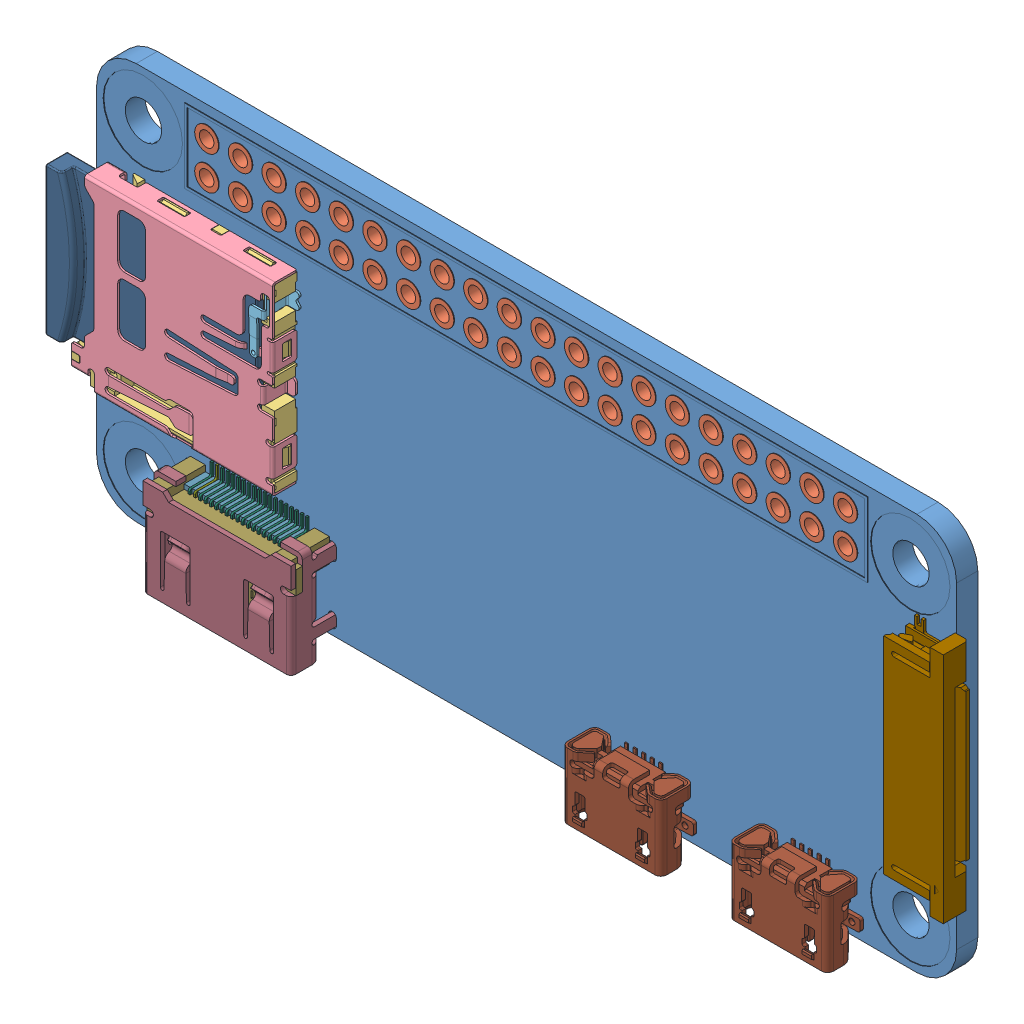
SolidWorks assembly rpi-zero, configuration Default. Lengths in mm.
Overall size (67.36 31 5.45).
80 component instances, 16 part files, 26 mates.
Components (placement in the parent):
- rpi-zero-board-2: rpi-zero-board [Default] at (32.5 15 0) size (65 30 1.65)
- rpi-zero-pin-header-pad-41: rpi-zero-pin-header-pad [Default] at (8.37 27.77 0.8) size (1.8 1.8 1.7)
- rpi-zero-micro-sd-slot.step-1: rpi-zero-micro-sd-slot.step [Default] at (7.6 15.665 1.65) x (0 1 0) z (1 0 0) size (14.1 1.9 15.45)
  - microSD_Body.step-1: microSD_Body.step [Default] at origin size (14.1 1.85 15.2)
  - microSD_Cover.step-1: microSD_Cover.step [Default] at (0 1.7 0) x (1 0 0) z (0 0 -1) size (13.95 1.9 15.2)
  - microSD_Card_Detect.step-1: microSD_Card_Detect.step [Default] at (4.99 -0.05 7.4) size (4.45 1.9 2.05)
  - microSD_Pin_11.15.step-1: microSD_Pin_11.15.step [Default] at (5.725 0 -2) x (0 0 1) z (-1 0 0) size (7.35 1.18 0.6)
  - microSD_Pin_11.15.step-2: microSD_Pin_11.15.step [Default] at (4.625 0 -2) x (0 0 1) z (-1 0 0) size (7.35 1.18 0.6)
  - microSD_Pin_11.35.step-1: microSD_Pin_11.35.step [Default] at (3.525 0 -2) x (0 0 1) z (-1 0 0) size (7.35 1.18 0.6)
  - microSD_Pin_11.15.step-3: microSD_Pin_11.15.step [Default] at (2.425 0 -2) x (0 0 1) z (-1 0 0) size (7.35 1.18 0.6)
  - microSD_Pin_11.35.step-2: microSD_Pin_11.35.step [Default] at (1.325 0 -2) x (0 0 1) z (-1 0 0) size (7.35 1.18 0.6)
  - microSD_Pin_11.15.step-4: microSD_Pin_11.15.step [Default] at (0.225 0 -2) x (0 0 1) z (-1 0 0) size (7.35 1.18 0.6)
  - microSD_Pin_10.75.step-1: microSD_Pin_10.75.step [Default] at (-0.875 0 -2) x (0 0 1) z (-1 0 0) size (7.25 1.18 0.6)
  - microSD_Pin_11.15.step-5: microSD_Pin_11.15.step [Default] at (-1.975 0 -2) x (0 0 1) z (-1 0 0) size (7.35 1.18 0.6)
- rpi-zero-fpc-connector.stp-1: rpi-zero-fpc-connector.stp [Default] at (61.5 15 1.61) x (0 1 0) z (1 0 0) size (17.6 2.04 5.2)
- rpi-zero-micro-sd.stp-3: rpi-zero-micro-sd.stp [Default] at (6.17 16.9 2.45) x (1 0 0) z (0 -1 0) size (15.06 1.66 11.19)
- rpi-zero-pin-header-pad-42: rpi-zero-pin-header-pad [Default] at (8.37 25.23 0.8) size (1.8 1.8 1.7)
- rpi-zero-pin-header-pad-43: rpi-zero-pin-header-pad [Default] at (10.91 27.77 0.8) size (1.8 1.8 1.7)
- rpi-zero-pin-header-pad-44: rpi-zero-pin-header-pad [Default] at (10.91 25.23 0.8) size (1.8 1.8 1.7)
- rpi-zero-pin-header-pad-45: rpi-zero-pin-header-pad [Default] at (13.45 27.77 0.8) size (1.8 1.8 1.7)
- rpi-zero-pin-header-pad-46: rpi-zero-pin-header-pad [Default] at (13.45 25.23 0.8) size (1.8 1.8 1.7)
- rpi-zero-pin-header-pad-47: rpi-zero-pin-header-pad [Default] at (15.99 27.77 0.8) size (1.8 1.8 1.7)
- rpi-zero-pin-header-pad-48: rpi-zero-pin-header-pad [Default] at (15.99 25.23 0.8) size (1.8 1.8 1.7)
- rpi-zero-pin-header-pad-49: rpi-zero-pin-header-pad [Default] at (18.53 27.77 0.8) size (1.8 1.8 1.7)
- rpi-zero-pin-header-pad-50: rpi-zero-pin-header-pad [Default] at (18.53 25.23 0.8) size (1.8 1.8 1.7)
- rpi-zero-pin-header-pad-51: rpi-zero-pin-header-pad [Default] at (21.07 27.77 0.8) size (1.8 1.8 1.7)
- rpi-zero-pin-header-pad-52: rpi-zero-pin-header-pad [Default] at (21.07 25.23 0.8) size (1.8 1.8 1.7)
- rpi-zero-pin-header-pad-53: rpi-zero-pin-header-pad [Default] at (23.61 27.77 0.8) size (1.8 1.8 1.7)
- rpi-zero-pin-header-pad-54: rpi-zero-pin-header-pad [Default] at (23.61 25.23 0.8) size (1.8 1.8 1.7)
- rpi-zero-pin-header-pad-55: rpi-zero-pin-header-pad [Default] at (26.15 27.77 0.8) size (1.8 1.8 1.7)
- rpi-zero-pin-header-pad-56: rpi-zero-pin-header-pad [Default] at (26.15 25.23 0.8) size (1.8 1.8 1.7)
- rpi-zero-pin-header-pad-57: rpi-zero-pin-header-pad [Default] at (28.69 27.77 0.8) size (1.8 1.8 1.7)
- rpi-zero-pin-header-pad-58: rpi-zero-pin-header-pad [Default] at (28.69 25.23 0.8) size (1.8 1.8 1.7)
- rpi-zero-pin-header-pad-59: rpi-zero-pin-header-pad [Default] at (31.23 27.77 0.8) size (1.8 1.8 1.7)
- rpi-zero-pin-header-pad-60: rpi-zero-pin-header-pad [Default] at (31.23 25.23 0.8) size (1.8 1.8 1.7)
- rpi-zero-pin-header-pad-61: rpi-zero-pin-header-pad [Default] at (33.77 27.77 0.8) size (1.8 1.8 1.7)
- rpi-zero-pin-header-pad-62: rpi-zero-pin-header-pad [Default] at (33.77 25.23 0.8) size (1.8 1.8 1.7)
- rpi-zero-pin-header-pad-63: rpi-zero-pin-header-pad [Default] at (36.31 27.77 0.8) size (1.8 1.8 1.7)
- rpi-zero-pin-header-pad-64: rpi-zero-pin-header-pad [Default] at (36.31 25.23 0.8) size (1.8 1.8 1.7)
- rpi-zero-pin-header-pad-65: rpi-zero-pin-header-pad [Default] at (38.85 27.77 0.8) size (1.8 1.8 1.7)
- rpi-zero-pin-header-pad-66: rpi-zero-pin-header-pad [Default] at (38.85 25.23 0.8) size (1.8 1.8 1.7)
- rpi-zero-pin-header-pad-67: rpi-zero-pin-header-pad [Default] at (41.39 27.77 0.8) size (1.8 1.8 1.7)
- rpi-zero-pin-header-pad-68: rpi-zero-pin-header-pad [Default] at (41.39 25.23 0.8) size (1.8 1.8 1.7)
- rpi-zero-pin-header-pad-69: rpi-zero-pin-header-pad [Default] at (43.93 27.77 0.8) size (1.8 1.8 1.7)
- rpi-zero-pin-header-pad-70: rpi-zero-pin-header-pad [Default] at (43.93 25.23 0.8) size (1.8 1.8 1.7)
- rpi-zero-pin-header-pad-71: rpi-zero-pin-header-pad [Default] at (46.47 27.77 0.8) size (1.8 1.8 1.7)
- rpi-zero-pin-header-pad-72: rpi-zero-pin-header-pad [Default] at (46.47 25.23 0.8) size (1.8 1.8 1.7)
- rpi-zero-pin-header-pad-73: rpi-zero-pin-header-pad [Default] at (49.01 27.77 0.8) size (1.8 1.8 1.7)
- rpi-zero-pin-header-pad-74: rpi-zero-pin-header-pad [Default] at (49.01 25.23 0.8) size (1.8 1.8 1.7)
- rpi-zero-pin-header-pad-75: rpi-zero-pin-header-pad [Default] at (51.55 27.77 0.8) size (1.8 1.8 1.7)
- rpi-zero-pin-header-pad-76: rpi-zero-pin-header-pad [Default] at (51.55 25.23 0.8) size (1.8 1.8 1.7)
- rpi-zero-pin-header-pad-77: rpi-zero-pin-header-pad [Default] at (54.09 27.77 0.8) size (1.8 1.8 1.7)
- rpi-zero-pin-header-pad-78: rpi-zero-pin-header-pad [Default] at (54.09 25.23 0.8) size (1.8 1.8 1.7)
- rpi-zero-pin-header-pad-79: rpi-zero-pin-header-pad [Default] at (56.63 27.77 0.8) size (1.8 1.8 1.7)
- rpi-zero-pin-header-pad-80: rpi-zero-pin-header-pad [Default] at (56.63 25.23 0.8) size (1.8 1.8 1.7)
- rpi-zero-micro-usb.stp-1: rpi-zero-micro-usb.stp [Default] at (-44 4.3 1.225) x (1 0 0) z (0 -1 0) size (7.91 2.77 5.21)
- rpi-zero-micro-usb.stp-2: rpi-zero-micro-usb.stp [Default] at (-56.6 4.3 1.225) x (1 0 0) z (0 -1 0) size (7.91 2.77 5.21)
- rpi-zero-hdmi.stp-1: rpi-zero-hdmi.stp [Default] at (12.4 5.5 3.1) x (0 -1 0) z (0 0 1) size (7.9 11.25 5.45)
  - 685119136923_Housing.stp-1: 685119136923_Housing.stp [Default] at origin size (5.5 11.25 2.9)
  - 685119136923_Shielding.stp-1: 685119136923_Shielding.stp [Default] at (2.875 0 0.82) x (0 1 0) z (0 0 1) size (11.21 7.6 5.45)
  - 685119136923_Housing2.stp-1: 685119136923_Housing2.stp [Default] at (-0.075 0 -0.65) x (0 -1 0) z (0 0 1) size (8.25 0.75 1.6)
  - 685119136923_Pin1.stp-1: 685119136923_Pin1.stp [Default] at (2.1 -3.6 0.3) size (5.9 0.15 1.8)
  - 685119136923_Pin1.stp-2: 685119136923_Pin1.stp [Default] at (2.1 -2.8 0.3) size (5.9 0.15 1.8)
  - 685119136923_Pin1.stp-3: 685119136923_Pin1.stp [Default] at (2.1 -2.4 0.3) size (5.9 0.15 1.8)
  - 685119136923_Pin1.stp-4: 685119136923_Pin1.stp [Default] at (2.1 -2 0.3) size (5.9 0.15 1.8)
  - 685119136923_Pin1.stp-5: 685119136923_Pin1.stp [Default] at (2.1 -1.6 0.3) size (5.9 0.15 1.8)
  - 685119136923_Pin1.stp-6: 685119136923_Pin1.stp [Default] at (2.1 -1.2 0.3) size (5.9 0.15 1.8)
  - 685119136923_Pin1.stp-7: 685119136923_Pin1.stp [Default] at (2.1 -0.8 0.3) size (5.9 0.15 1.8)
  - 685119136923_Pin1.stp-8: 685119136923_Pin1.stp [Default] at (2.1 -0.4 0.3) size (5.9 0.15 1.8)
  - 685119136923_Pin1.stp-9: 685119136923_Pin1.stp [Default] at (2.1 0 0.3) size (5.9 0.15 1.8)
  - 685119136923_Pin1.stp-10: 685119136923_Pin1.stp [Default] at (2.1 0.4 0.3) size (5.9 0.15 1.8)
  - 685119136923_Pin1.stp-11: 685119136923_Pin1.stp [Default] at (2.1 0.8 0.3) size (5.9 0.15 1.8)
  - 685119136923_Pin1.stp-12: 685119136923_Pin1.stp [Default] at (2.1 1.2 0.3) size (5.9 0.15 1.8)
  - 685119136923_Pin1.stp-13: 685119136923_Pin1.stp [Default] at (2.1 1.6 0.3) size (5.9 0.15 1.8)
  - 685119136923_Pin1.stp-14: 685119136923_Pin1.stp [Default] at (2.1 2 0.3) size (5.9 0.15 1.8)
  - 685119136923_Pin1.stp-15: 685119136923_Pin1.stp [Default] at (2.1 2.4 0.3) size (5.9 0.15 1.8)
  - 685119136923_Pin1.stp-16: 685119136923_Pin1.stp [Default] at (2.1 2.8 0.3) size (5.9 0.15 1.8)
  - 685119136923_Pin1.stp-17: 685119136923_Pin1.stp [Default] at (2.1 3.2 0.3) size (5.9 0.15 1.8)
  - 685119136923_Pin1.stp-18: 685119136923_Pin1.stp [Default] at (2.1 3.6 0.3) size (5.9 0.15 1.8)
  - 685119136923_Pin2.stp-1: 685119136923_Pin2.stp [Default] at (1.7983 -3.2 0.3) size (5.3 0.15 1.8)
Mates (geometry in assembly coordinates):
- Coincident1: coincident anti-aligned: plane of rpi-zero-board-2 through (0 27 1.6) normal (-1 0 0)
- Coincident2: coincident anti-aligned: plane of rpi-zero-board-2 through (3 0 1.6) normal (0 -1 0)
- Coincident3: coincident anti-aligned: plane of rpi-zero-board-2 through (62 27 0) normal (0 0 -1)
- Concentric1: concentric anti-aligned: cylinder of rpi-zero-board-2 through (8.37 27.77 -0.001) axis (0 0 1) radius 0.6; cylinder of rpi-zero-pin-header-pad-41 through (8.37 27.77 0.8) axis (0 0 -1) radius 0.6
- Coincident4: coincident anti-aligned: plane of rpi-zero-board-2 through (62 27 1.6) normal (0 0 1); plane of rpi-zero-pin-header-pad-41 through (7.77 27.77 1.6) normal (0 0 -1)
- Parallel1: parallel aligned: plane of rpi-zero-pin-header-pad-41 through (8.37 27.77 0.8) normal (0 1 0)
- Coincident6: coincident anti-aligned: plane of rpi-zero-board-2 through (62 27 1.6) normal (0 0 1); plane of rpi-zero-micro-sd-slot.step-1/microSD_Card_Detect.step-1 through (15.25 20.255 1.6) normal (0 0 -1)
- Coincident7: coincident anti-aligned: plane of rpi-zero-board-2 through (62 27 1.6) normal (0 0 1); plane of rpi-zero-fpc-connector.stp-1 through (62.85 8.805 1.6) normal (0 0 -1)
- Distance1: distance = 1 mm aligned: plane of rpi-zero-fpc-connector.stp-1 through (66 15 1.61) normal (1 0 0); plane of rpi-zero-board-2 through (65 27 1.6) normal (1 0 0)
- Distance2: distance = 15 mm: point of rpi-zero-fpc-connector.stp-1; plane of rpi-zero-board-2 through (3 0 1.6) normal (0 -1 0)
- Coincident10: coincident aligned: plane of rpi-zero-board-2 through (0 27 1.6) normal (-1 0 0); plane of rpi-zero-micro-sd-slot.step-1/microSD_Body.step-1 through (0 8.84 3.35) normal (-1 0 0)
- Distance3: distance = 0.5 mm anti-aligned: plane of rpi-zero-micro-sd.stp-3 through (13.7 12.74 2.45) normal (1 0 0); plane of rpi-zero-micro-sd-slot.step-1/microSD_Body.step-1 through (14.2 22.49 -16.7005) normal (-1 0 0)
- Distance4: distance = 0 mm: plane of rpi-zero-micro-sd.stp-3 through (11.23 21.64 2.45) normal (0 0 -1); cylinder of rpi-zero-micro-sd-slot.step-1/microSD_Pin_10.75.step-1 through (11.1211 14.79 2.45) axis (0 1 0) radius 0.35
- Coincident12: coincident anti-aligned: plane of rpi-zero-micro-sd-slot.step-1/microSD_Cover.step-1 through (7.6 22.49 3.35) normal (0 -1 0); plane of rpi-zero-micro-sd.stp-3 through (13.7 22.49 2.45) normal (0 1 0)
- Distance5: distance = 16.9 mm: unknown of rpi-zero-micro-sd.stp-3; plane of rpi-zero-board-2 through (3 0 1.6) normal (0 -1 0)
- Parallel4: parallel anti-aligned: plane of rpi-zero-board-2 through (3 0 1.6) normal (0 -1 0); plane of rpi-zero-micro-usb.stp-2 through (41.4 4.05 3.1) normal (0 1 0)
- Distance7: distance = 41.4 mm: unknown of rpi-zero-micro-usb.stp-2; plane of rpi-zero-board-2 through (0 27 1.6) normal (-1 0 0)
- Coincident13: coincident anti-aligned: plane of rpi-zero-board-2 through (62 27 1.6) normal (0 0 1); plane of rpi-zero-micro-usb.stp-1 through (57.025 3.55 1.6) normal (0 0 -1)
- Distance8: distance = 54 mm: unknown of rpi-zero-micro-usb.stp-1; plane of rpi-zero-board-2 through (0 27 1.6) normal (-1 0 0)
- Parallel5: parallel anti-aligned: plane of rpi-zero-board-2 through (3 0 1.6) normal (0 -1 0); plane of rpi-zero-micro-usb.stp-1 through (54 4.05 3.1) normal (0 1 0)
- Coincident16: coincident anti-aligned: plane of rpi-zero-board-2 through (62 27 1.6) normal (0 0 1); plane of rpi-zero-micro-usb.stp-2 through (38.375 3.55 1.6) normal (0 0 -1)
- Distance9: distance = 1 mm aligned: plane of rpi-zero-micro-usb.stp-2 through (41.4 -1 2.85) normal (0 -1 0); plane of rpi-zero-board-2 through (3 0 1.6) normal (0 -1 0)
- Distance10: distance = 1 mm aligned: plane of rpi-zero-micro-usb.stp-1 through (54 -1 2.85) normal (0 -1 0); plane of rpi-zero-board-2 through (3 0 1.6) normal (0 -1 0)
- Coincident17: coincident anti-aligned: plane of rpi-zero-board-2 through (62 27 1.6) normal (0 0 1); plane of rpi-zero-hdmi.stp-1/685119136923_Pin1.stp-10 through (12.875 6.12 1.6) normal (0 0 -1)
- Distance11: distance = 1 mm aligned: plane of rpi-zero-hdmi.stp-1/685119136923_Shielding.stp-1 through (12.395 -1 1.7) normal (0 -1 0); plane of rpi-zero-board-2 through (3 0 1.6) normal (0 -1 0)
- Distance12: distance = 12.4 mm: unknown of rpi-zero-hdmi.stp-1/685119136923_Shielding.stp-1; plane of rpi-zero-board-2 through (0 27 1.6) normal (-1 0 0)
